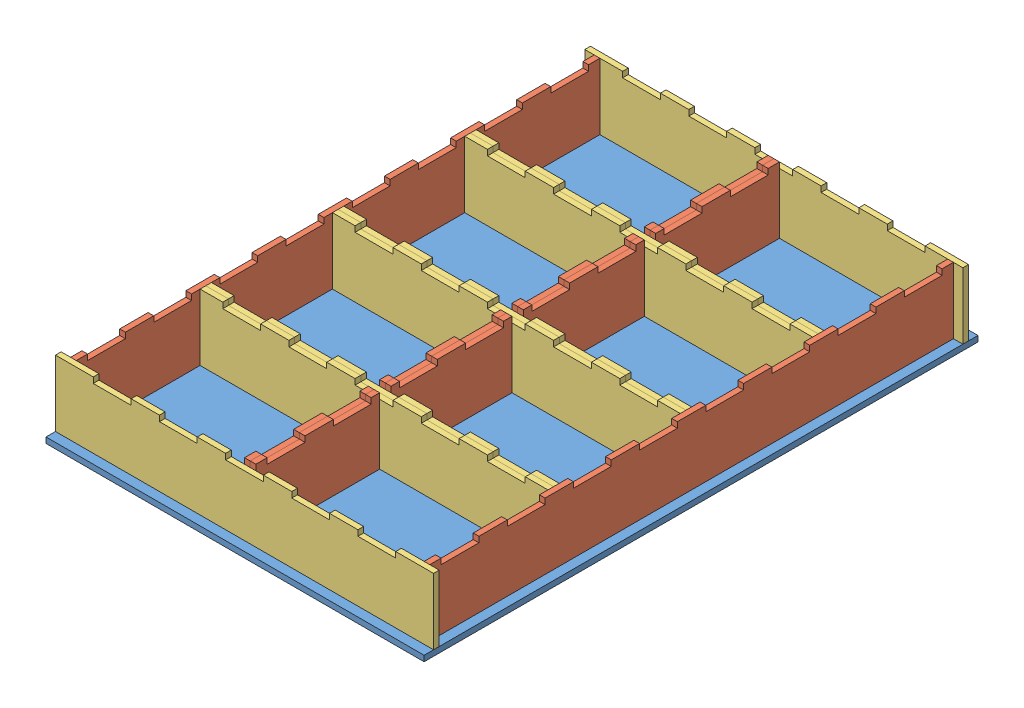
SolidWorks assembly Assem1, configuration Default. Lengths in mm.
Overall size (200 38 293).
19 component instances, 3 part files, 54 mates.
Components (placement in the parent):
- base-1: base [Default] at (16.4212 149.2181 390.9951) size (200 3 293)
- long_side-1: long_side [Default] at (21.4212 152.2181 382.9951) size (3 38 277)
- side-1: side [Default] at (16.4212 152.2181 102.9951) x (1 0 0) z (0 0 -1) size (200 38 3)
- long_side-2: long_side [Default] at (208.4212 152.2181 382.9951) size (3 38 277)
- side-2: side [Default] at (16.4212 152.2181 382.9951) x (1 0 0) z (0 0 -1) size (200 38 3)
- side-3: side [inside] at (208.4212 152.2181 177.4951) x (-1 0 0) z (0 0 1) size (184 38 3)
- side-4: side [inside] at (208.4212 152.2181 174.4951) x (-1 0 0) z (0 0 1) size (184 38 3)
- side-5: side [inside] at (208.4212 152.2181 314.4951) x (-1 0 0) z (0 0 1) size (184 38 3)
- side-6: side [inside] at (208.4212 152.2181 244.4951) x (-1 0 0) z (0 0 1) size (184 38 3)
- side-7: side [inside] at (24.4212 152.2181 244.4951) x (1 0 0) z (0 0 -1) size (184 38 3)
- side-8: side [inside] at (208.4212 152.2181 317.4951) x (-1 0 0) z (0 0 1) size (184 38 3)
- long_side-3: long_side [inside] at (113.4212 152.2181 382.9951) size (3 38 65.5)
- long_side-5: long_side [inside_middle] at (116.4212 152.2181 177.4951) x (-1 0 0) z (0 0 -1) size (3 38 64)
- long_side-7: long_side [inside_middle] at (116.4212 152.2181 241.4951) size (3 38 64)
- long_side-8: long_side [inside_middle] at (116.4212 152.2181 311.4951) size (3 38 64)
- long_side-9: long_side [inside_middle] at (113.4212 152.2181 311.4951) size (3 38 64)
- long_side-10: long_side [inside] at (116.4212 152.2181 382.9951) size (3 38 65.5)
- long_side-11: long_side [inside] at (116.4212 152.2181 105.9951) x (-1 0 0) z (0 0 -1) size (3 38 65.5)
- long_side-12: long_side [inside] at (119.4212 152.2181 105.9951) x (-1 0 0) z (0 0 -1) size (3 38 65.5)
Mates (geometry in assembly coordinates):
- Coincident2: coincident anti-aligned: plane of base-1 through (156.4212 142.2181 102.9951) normal (0 0 1); plane of side-1 through (16.4212 152.2181 102.9951) normal (0 0 -1)
- Coincident3: coincident aligned: plane of base-1 through (216.4212 152.2181 390.9951) normal (1 0 0); plane of side-1 through (216.4212 152.2181 105.9951) normal (1 0 0)
- Coincident4: coincident anti-aligned: plane of base-1 through (16.4212 152.2181 390.9951) normal (0 1 0); plane of side-1 through (196.4212 152.2181 105.9951) normal (0 -1 0)
- Coincident5: coincident anti-aligned: plane of base-1 through (24.4212 142.2181 460.9951) normal (-1 0 0); plane of long_side-1 through (24.4212 152.2181 382.9951) normal (1 0 0)
- Coincident6: coincident anti-aligned: plane of long_side-1 through (24.4212 152.2181 105.9951) normal (0 0 -1); plane of side-1 through (16.4212 152.2181 105.9951) normal (0 0 1)
- Coincident7: coincident aligned: plane of base-1 through (16.4212 149.2181 390.9951) normal (0 -1 0); plane of long_side-1 through (24.4212 149.2181 376.9951) normal (0 -1 0)
- Coincident9: coincident aligned: plane of base-1 through (216.4212 152.2181 390.9951) normal (1 0 0); plane of side-2 through (216.4212 152.2181 385.9951) normal (1 0 0)
- Coincident11: coincident aligned: plane of base-1 through (16.4212 149.2181 390.9951) normal (0 -1 0); plane of side-2 through (71.4212 149.2181 385.9951) normal (0 -1 0)
- Coincident14: coincident aligned: plane of base-1 through (16.4212 149.2181 390.9951) normal (0 -1 0); plane of long_side-2 through (211.4212 149.2181 131.9951) normal (0 -1 0)
- Coincident15: coincident anti-aligned: plane of side-1 through (16.4212 152.2181 105.9951) normal (0 0 1); plane of long_side-2 through (211.4212 152.2181 105.9951) normal (0 0 -1)
- Coincident16: coincident anti-aligned: plane of base-1 through (211.4212 142.2181 600.9951) normal (-1 0 0); plane of long_side-2 through (211.4212 152.2181 382.9951) normal (1 0 0)
- Coincident17: coincident anti-aligned: plane of base-1 through (16.4212 152.2181 390.9951) normal (0 1 0); plane of side-3 through (106.4212 152.2181 174.4951) normal (0 -1 0)
- Coincident18: coincident anti-aligned: plane of long_side-2 through (208.4212 152.2181 382.9951) normal (-1 0 0); plane of side-3 through (208.4212 152.2181 174.4951) normal (1 0 0)
- Coincident19: coincident anti-aligned: plane of base-1 through (36.4212 142.2181 177.4951) normal (0 0 -1); plane of side-3 through (208.4212 152.2181 177.4951) normal (0 0 1)
- Coincident20: coincident anti-aligned: plane of base-1 through (16.4212 152.2181 390.9951) normal (0 1 0); plane of side-4 through (208.4212 152.2181 171.4951) normal (0 -1 0)
- Coincident21: coincident anti-aligned: plane of side-3 through (208.4212 152.2181 174.4951) normal (0 0 -1); plane of side-4 through (208.4212 152.2181 174.4951) normal (0 0 1)
- Coincident22: coincident aligned: plane of side-3 through (106.4212 187.2181 174.4951) normal (0 1 0); plane of side-4 through (208.4212 187.2181 171.4951) normal (0 1 0)
- Coincident23: coincident anti-aligned: plane of long_side-2 through (208.4212 152.2181 382.9951) normal (-1 0 0); plane of side-4 through (208.4212 152.2181 171.4951) normal (1 0 0)
- Coincident24: coincident anti-aligned: plane of base-1 through (141.4212 142.2181 247.4951) normal (0 0 -1); plane of side-7 through (24.4212 152.2181 247.4951) normal (0 0 1)
- Coincident25: coincident anti-aligned: plane of base-1 through (16.4212 152.2181 390.9951) normal (0 1 0); plane of side-7 through (91.4212 152.2181 247.4951) normal (0 -1 0)
- Coincident26: coincident anti-aligned: plane of long_side-1 through (24.4212 152.2181 382.9951) normal (1 0 0); plane of side-7 through (24.4212 152.2181 247.4951) normal (-1 0 0)
- Coincident27: coincident aligned: plane of base-1 through (16.4212 149.2181 390.9951) normal (0 -1 0); plane of side-6 through (196.4212 149.2181 241.4951) normal (0 -1 0)
- Coincident28: coincident anti-aligned: plane of side-6 through (208.4212 152.2181 244.4951) normal (0 0 1); plane of side-7 through (24.4212 152.2181 244.4951) normal (0 0 -1)
- Coincident29: coincident anti-aligned: plane of long_side-2 through (208.4212 152.2181 382.9951) normal (-1 0 0); plane of side-6 through (208.4212 152.2181 241.4951) normal (1 0 0)
- Coincident30: coincident anti-aligned: plane of base-1 through (16.4212 152.2181 390.9951) normal (0 1 0); plane of side-5 through (176.4212 152.2181 311.4951) normal (0 -1 0)
- Coincident31: coincident anti-aligned: plane of long_side-2 through (208.4212 152.2181 382.9951) normal (-1 0 0); plane of side-5 through (208.4212 152.2181 311.4951) normal (1 0 0)
- Coincident32: coincident anti-aligned: plane of base-1 through (141.4212 142.2181 311.4951) normal (0 0 1); plane of side-5 through (208.4212 152.2181 311.4951) normal (0 0 -1)
- Coincident33: coincident anti-aligned: plane of base-1 through (16.4212 152.2181 390.9951) normal (0 1 0); plane of side-8 through (141.4212 152.2181 314.4951) normal (0 -1 0)
- Coincident34: coincident anti-aligned: plane of long_side-2 through (208.4212 152.2181 382.9951) normal (-1 0 0); plane of side-8 through (208.4212 152.2181 314.4951) normal (1 0 0)
- Coincident35: coincident anti-aligned: plane of side-5 through (208.4212 152.2181 314.4951) normal (0 0 1); plane of side-8 through (208.4212 152.2181 314.4951) normal (0 0 -1)
- Coincident37: coincident anti-aligned: plane of base-1 through (119.4212 142.2181 286.9951) normal (-1 0 0); plane of long_side-8 through (119.4212 152.2181 311.4951) normal (1 0 0)
- Coincident38: coincident anti-aligned: plane of side-7 through (24.4212 152.2181 247.4951) normal (0 0 1); plane of long_side-8 through (109.4212 192.2181 247.4951) normal (0 0 -1)
- Coincident39: coincident aligned: plane of base-1 through (16.4212 149.2181 390.9951) normal (0 -1 0); plane of long_side-8 through (119.4212 149.2181 271.9951) normal (0 -1 0)
- Coincident40: coincident anti-aligned: plane of long_side-7 through (119.4212 152.2181 241.4951) normal (1 0 0); plane of base-1 through (119.4212 142.2181 216.9951) normal (-1 0 0)
- Coincident41: coincident anti-aligned: plane of side-3 through (208.4212 152.2181 177.4951) normal (0 0 1); plane of long_side-7 through (109.4212 192.2181 177.4951) normal (0 0 -1)
- Coincident42: coincident aligned: plane of long_side-7 through (119.4212 187.2181 216.9951) normal (0 1 0); plane of long_side-8 through (119.4212 187.2181 286.9951) normal (0 1 0)
- Coincident43: coincident anti-aligned: plane of base-1 through (113.4212 142.2181 216.9951) normal (1 0 0); plane of long_side-9 through (113.4212 152.2181 311.4951) normal (-1 0 0)
- Coincident45: coincident aligned: plane of long_side-8 through (119.4212 184.2181 306.9951) normal (0 1 0); plane of long_side-9 through (116.4212 184.2181 306.9951) normal (0 1 0)
- Coincident46: coincident anti-aligned: plane of side-5 through (208.4212 152.2181 311.4951) normal (0 0 -1); plane of long_side-9 through (116.4212 152.2181 311.4951) normal (0 0 1)
- Coincident47: coincident anti-aligned: plane of long_side-5 through (116.4212 152.2181 177.4951) normal (1 0 0); plane of long_side-7 through (116.4212 152.2181 241.4951) normal (-1 0 0)
- Coincident48: coincident anti-aligned: plane of side-6 through (208.4212 152.2181 241.4951) normal (0 0 -1); plane of long_side-5 through (123.4212 192.2181 241.4951) normal (0 0 1)
- Coincident49: coincident aligned: plane of long_side-5 through (113.4212 187.2181 201.9951) normal (0 1 0); plane of long_side-7 through (119.4212 187.2181 216.9951) normal (0 1 0)
- Coincident50: coincident anti-aligned: plane of base-1 through (119.4212 142.2181 321.9951) normal (-1 0 0); plane of long_side-10 through (119.4212 152.2181 382.9951) normal (1 0 0)
- Coincident51: coincident aligned: plane of long_side-9 through (116.4212 187.2181 286.9951) normal (0 1 0); plane of long_side-10 through (119.4212 187.2181 356.9951) normal (0 1 0)
- Coincident52: coincident anti-aligned: plane of side-8 through (208.4212 152.2181 317.4951) normal (0 0 1); plane of long_side-10 through (109.4212 192.2181 317.4951) normal (0 0 -1)
- Coincident53: coincident anti-aligned: plane of long_side-3 through (116.4212 152.2181 382.9951) normal (1 0 0); plane of long_side-10 through (116.4212 152.2181 382.9951) normal (-1 0 0)
- Coincident54: coincident aligned: plane of long_side-3 through (116.4212 187.2181 356.9951) normal (0 1 0); plane of long_side-10 through (119.4212 187.2181 356.9951) normal (0 1 0)
- Coincident55: coincident: plane of side-8 through (208.4212 152.2181 317.4951) normal (0 0 1); moEndPointRef_w of long_side-3
- Coincident56: coincident anti-aligned: plane of base-1 through (113.4212 142.2181 111.9951) normal (1 0 0); plane of long_side-11 through (113.4212 152.2181 105.9951) normal (-1 0 0)
- Coincident57: coincident anti-aligned: plane of side-4 through (208.4212 152.2181 171.4951) normal (0 0 -1); plane of long_side-11 through (123.4212 192.2181 171.4951) normal (0 0 1)
- Coincident58: coincident: line of long_side-5 through (116.4212 187.2181 201.9951) axis (0 0 1); plane of long_side-11 through (113.4212 187.2181 131.9951) normal (0 1 0)
- Coincident59: coincident anti-aligned: plane of side-1 through (16.4212 152.2181 105.9951) normal (0 0 1); plane of long_side-12 through (116.4212 152.2181 105.9951) normal (0 0 -1)
- Coincident60: coincident aligned: plane of long_side-11 through (113.4212 187.2181 131.9951) normal (0 1 0); plane of long_side-12 through (116.4212 187.2181 131.9951) normal (0 1 0)
- Coincident61: coincident anti-aligned: plane of long_side-11 through (116.4212 152.2181 105.9951) normal (1 0 0); plane of long_side-12 through (116.4212 152.2181 105.9951) normal (-1 0 0)
